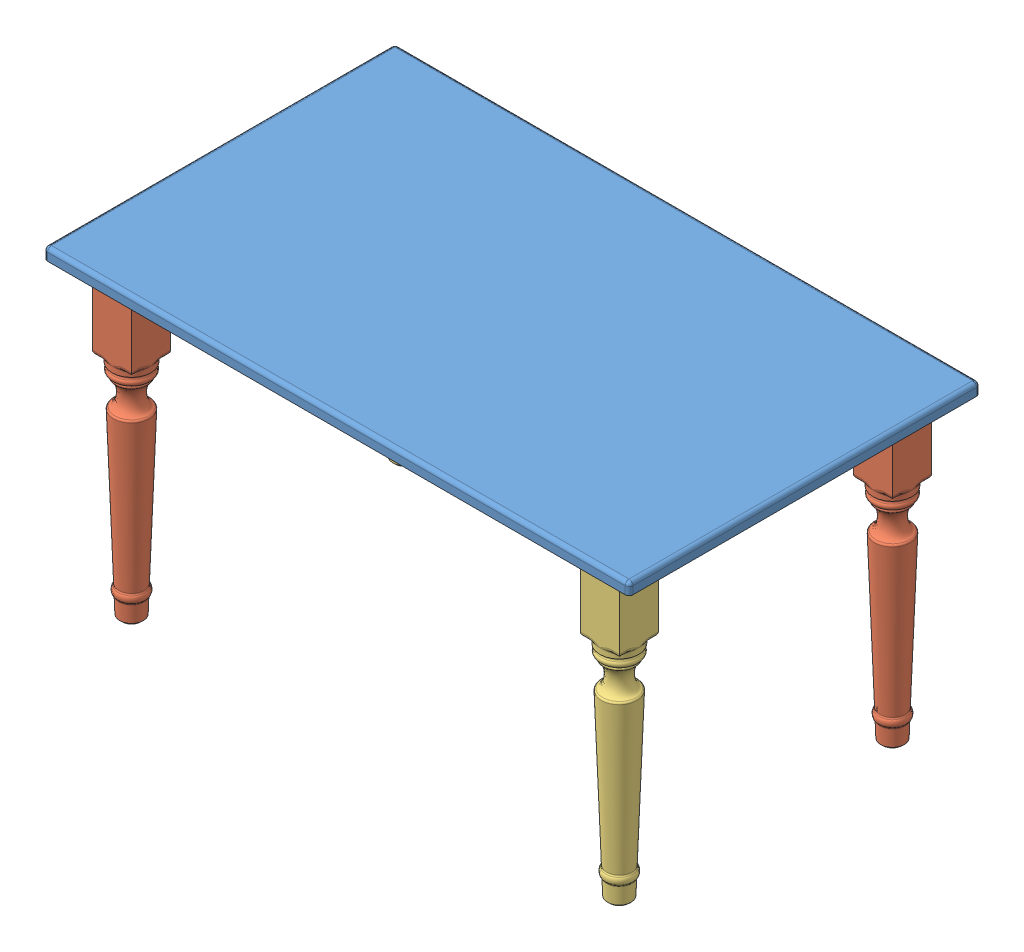
SolidWorks assembly Assemblage table, configuration Défaut. Lengths in mm.
Overall size (1500 810 900).
9 component instances, 5 part files, 24 mates.
Components (placement in the parent):
- Plan de table-1: Plan de table [Défaut] at (-844.6546 -18.7985 450) size (1500 30 900)
- Pied de table-1: Pied de table [Défaut] at (-719.6546 -798.7985 350) size (100 790 100)
- Pied de table-5: Pied de table [Défaut] at (530.3454 -798.7985 -350) x (-1 0 0) z (0 0 -1) size (100 790 100)
- Pied de table - 2-1: Pied de table - 2 [Défaut] at (-719.6546 -798.7985 -350) x (-1 0 0) z (0 0 -1) size (100 790 100)
- Pied de table - 2-2: Pied de table - 2 [Défaut] at (530.3454 -798.7985 350) size (100 790 100)
- Renfort court-1: Renfort court [Défaut] at (-734.6546 -43.7985 0) x (0 0 -1) z (1 0 0) size (620 50 30)
- Renfort long-1: Renfort long [Défaut] at (-94.6546 -43.7985 -365) size (1170 50 30)
- Renfort long-2: Renfort long [Défaut] at (-94.6546 -43.7985 335) size (1170 50 30)
- Renfort court-2: Renfort court [Défaut] at (515.3454 -43.7985 0) x (0 0 -1) z (1 0 0) size (620 50 30)
Mates (geometry in assembly coordinates):
- Coaxiale1: concentric aligned: cylinder of Plan de table-1 through (-744.6546 -3.7985 350) axis (0 -1 0) radius 10; cylinder of Pied de table-1 through (-744.6546 -8.7985 350) axis (0 -1 0) radius 10
- Coïncidente1: coincident anti-aligned: plane of Plan de table-1 through (-744.6546 -3.7985 360) normal (0 0 -1); plane of Pied de table-1 through (-744.6546 -8.7985 360) normal (0 0 1)
- Coïncidente2: coincident anti-aligned: plane of Plan de table-1 through (-844.6546 -18.7985 450) normal (0 -1 0); plane of Pied de table-1 through (-719.6546 -18.7985 350) normal (0 1 0)
- Coaxiale2: concentric aligned: cylinder of Plan de table-1 through (555.3454 -3.7985 -350) axis (0 -1 0) radius 10; cylinder of Pied de table-5 through (555.3454 -8.7985 -350) axis (0 -1 0) radius 10
- Coïncidente3: coincident anti-aligned: plane of Plan de table-1 through (555.3454 -3.7985 -360) normal (0 0 1); plane of Pied de table-5 through (555.3454 -8.7985 -360) normal (0 0 -1)
- Coïncidente4: coincident anti-aligned: plane of Plan de table-1 through (-844.6546 -18.7985 450) normal (0 -1 0); plane of Pied de table-5 through (530.3454 -18.7985 -350) normal (0 1 0)
- Coaxiale3: concentric aligned: cylinder of Plan de table-1 through (-744.6546 -3.7985 -350) axis (0 -1 0) radius 10; cylinder of Pied de table - 2-1 through (-744.6546 -8.7985 -350) axis (0 -1 0) radius 10
- Coïncidente5: coincident anti-aligned: plane of Plan de table-1 through (-744.6546 -3.7985 -360) normal (0 0 1); plane of Pied de table - 2-1 through (-694.6546 -8.7985 -360) normal (0 0 -1)
- Coïncidente6: coincident anti-aligned: plane of Plan de table-1 through (-844.6546 -18.7985 450) normal (0 -1 0); plane of Pied de table - 2-1 through (-719.6546 -18.7985 -350) normal (0 1 0)
- Coaxiale4: concentric aligned: cylinder of Plan de table-1 through (505.3454 -3.7985 350) axis (0 -1 0) radius 10; cylinder of Pied de table - 2-2 through (505.3454 -8.7985 350) axis (0 -1 0) radius 10
- Coïncidente7: coincident anti-aligned: plane of Plan de table-1 through (555.3454 -3.7985 360) normal (0 0 -1); plane of Pied de table - 2-2 through (505.3454 -8.7985 360) normal (0 0 1)
- Coïncidente8: coincident anti-aligned: plane of Plan de table-1 through (-844.6546 -18.7985 450) normal (0 -1 0); plane of Pied de table - 2-2 through (530.3454 -18.7985 350) normal (0 1 0)
- Coaxiale5: concentric aligned: cylinder of Pied de table-1 through (-719.6546 -53.7985 315) axis (0 0 -1) radius 6; cylinder of Renfort court-1 through (-719.6546 -53.7985 310) axis (0 0 -1) radius 6
- Coïncidente9: coincident anti-aligned: plane of Pied de table-1 through (-725.6546 -33.7985 315) normal (1 0 0); plane of Renfort court-1 through (-725.6546 -33.7985 310) normal (-1 0 0)
- Coïncidente10: coincident anti-aligned: plane of Pied de table-1 through (-769.6546 -18.7985 300) normal (0 0 -1); plane of Renfort court-1 through (-704.6546 -18.7985 300) normal (0 0 1)
- Coaxiale6: concentric aligned: cylinder of Pied de table-5 through (495.3454 -53.7985 -350) axis (-1 0 0) radius 6; cylinder of Renfort long-1 through (490.3454 -53.7985 -350) axis (-1 0 0) radius 6
- Coïncidente11: coincident anti-aligned: plane of Pied de table-5 through (495.3454 -33.7985 -356) normal (0 0 1); plane of Renfort long-1 through (490.3454 -33.7985 -356) normal (0 0 -1)
- Coïncidente12: coincident anti-aligned: plane of Pied de table-5 through (480.3454 -18.7985 -300) normal (-1 0 0); plane of Renfort long-1 through (480.3454 -18.7985 -335) normal (1 0 0)
- Coaxiale7: concentric aligned: cylinder of Pied de table-1 through (-684.6546 -53.7985 350) axis (1 0 0) radius 6; cylinder of Renfort long-2 through (-679.6546 -53.7985 350) axis (1 0 0) radius 6
- Coïncidente13: coincident anti-aligned: plane of Pied de table-1 through (-684.6546 -33.7985 356) normal (0 0 -1); plane of Renfort long-2 through (-679.6546 -33.7985 356) normal (0 0 1)
- Coïncidente14: coincident anti-aligned: plane of Pied de table-1 through (-669.6546 -18.7985 300) normal (1 0 0); plane of Renfort long-2 through (-669.6546 -18.7985 365) normal (-1 0 0)
- Coïncidente15: coincident anti-aligned: plane of Pied de table - 2-2 through (536.3454 -33.7985 315) normal (-1 0 0); plane of Renfort court-2 through (536.3454 -33.7985 310) normal (1 0 0)
- Coaxiale8: concentric aligned: cylinder of Pied de table - 2-2 through (530.3454 -53.7985 315) axis (0 0 -1) radius 6; cylinder of Renfort court-2 through (530.3454 -53.7985 310) axis (0 0 -1) radius 6
- Coïncidente16: coincident anti-aligned: plane of Pied de table - 2-2 through (480.3454 -18.7985 300) normal (0 0 -1); plane of Renfort court-2 through (545.3454 -18.7985 300) normal (0 0 1)
